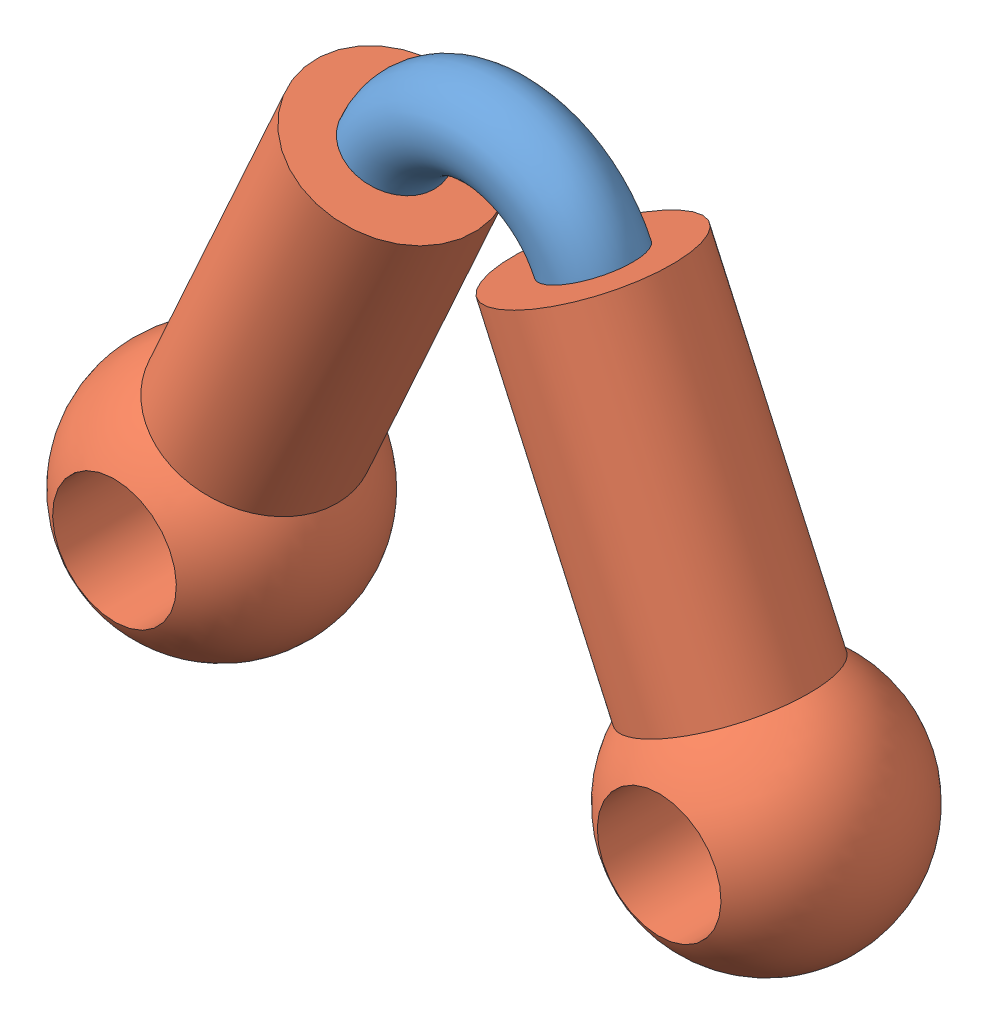
SolidWorks assembly makeshift, configuration Default. Lengths in mm.
Overall size (35.23 26.44 8.66).
3 component instances, 2 part files, 5 mates.
Components (placement in the parent):
- link_joint-1: link_joint [Default] at (-4.0116 21.0043 6.8918) size (19.42 14.17 3.5)
- ball_joint-1: ball_joint [Default] at (-15.0116 -3.3401 6.8918) x (-0.91129 0.411765 0) z (0 0 1) size (10 22 8.66)
- ball_joint-2: ball_joint [Default] at (6.9884 -3.3401 6.8918) x (-0.91129 -0.411765 0) z (0 0 1) size (10 22 8.66)
Mates (geometry in assembly coordinates):
- Concentric1: concentric aligned: cylinder of link_joint-1 through (-12.1292 3.0389 6.8918) axis (0.411765 0.91129 0) radius 1.75; cylinder of ball_joint-1 through (-15.0116 -3.3401 6.8918) axis (0.411765 0.91129 0) radius 3.5
- Concentric2: concentric anti-aligned: cylinder of link_joint-1 through (-0.0116 12.1518 6.8918) axis (0.411765 -0.91129 0) radius 1.75; cylinder of ball_joint-2 through (6.9884 -3.3401 6.8918) axis (-0.411765 0.91129 0) radius 3.5
- Coincident1: coincident aligned: circle of link_joint-1; circle of ball_joint-2
- Coincident2: coincident anti-aligned: circle of link_joint-1; circle of ball_joint-1
- Coincident3: coincident aligned: plane of ball_joint-1 through (-15.0116 -3.3401 6.8918) normal (0 0 1); plane of ball_joint-2 through (6.9884 -3.3401 6.8918) normal (0 0 1)
